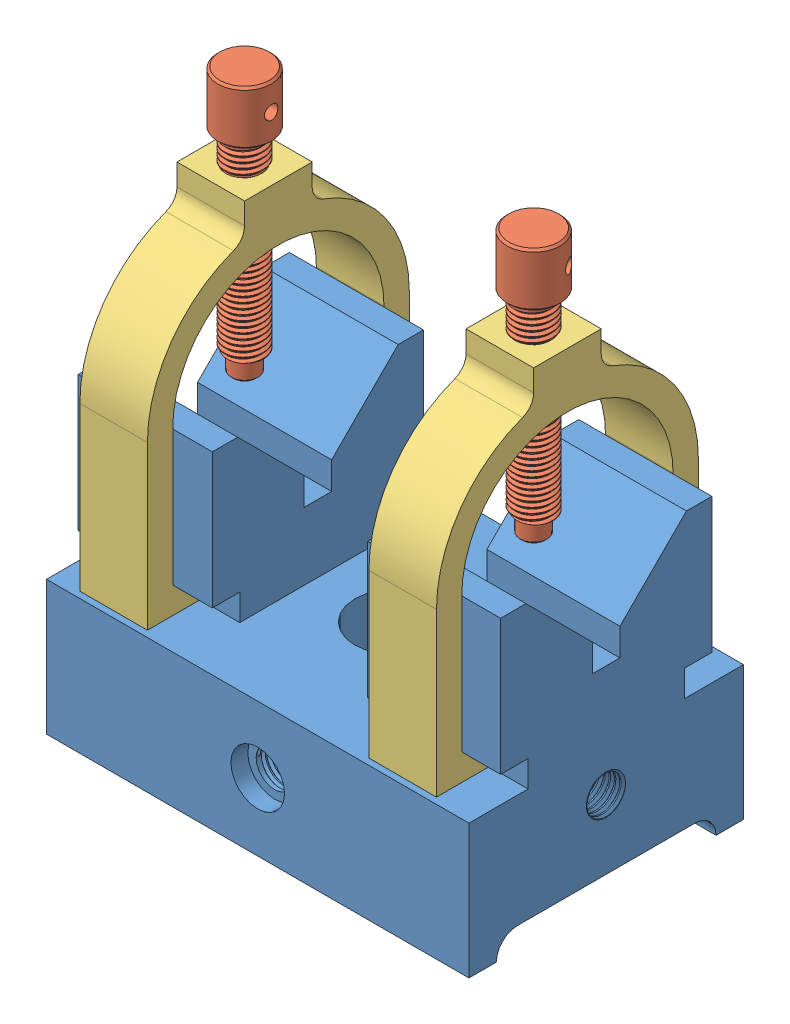
SolidWorks assembly Assem1, configuration Default. Lengths in mm.
Overall size (100.48 128.94 65).
5 component instances, 3 part files, 6 mates.
Components (placement in the parent):
- 1.Base-1: 1.Base [Default] at (-55.5589 15.6403 18.5643) size (100.48 70 65)
- 2.Fastener-1: 2.Fastener [Default] at (-22.7369 109.5842 18.5643) x (-0.457511 0 -0.889204) z (0.889204 0 -0.457511) size (12.7 62.7 12.7)
- 3.U-Clamp-1: 3.U-Clamp [Default] at (-22.7369 50.8903 18.5643) size (16 76.98 62)
- 3.U-Clamp-2: 3.U-Clamp [Default] at (-91.171 50.8903 18.5643) size (16 76.98 62)
- 2.Fastener-2: 2.Fastener [Default] at (-91.171 108.5473 18.5643) x (-0.023523 0 -0.999723) z (0.999723 0 -0.023523) size (12.7 62.7 12.7)
Mates (geometry in assembly coordinates):
- Coincident1: coincident anti-aligned: plane of 1.Base-1 through (-105.5589 12.3903 18.5643) normal (0 1 0); plane of 3.U-Clamp-1 through (-14.7369 12.3903 49.5643) normal (0 -1 0)
- Width1: width anti-aligned: plane of 3.U-Clamp-1 through (-14.7369 50.8903 49.5643) normal (0 0 1); plane of 1.Base-1 through (-14.7369 50.8903 -12.4357) normal (0 0 -1); plane of 3.U-Clamp-1 through (-105.5589 15.6403 -6.4357) normal (0 0 -1); plane of 1.Base-1 through (-105.5589 15.6403 43.5643) normal (0 0 1)
- Screw1: screw = 1 aligned: cylinder of 2.Fastener-1 through (-22.7369 51.8842 18.5643) axis (0 1 0) radius 4.625; cylinder of 3.U-Clamp-1 through (-22.7369 56.1903 18.5643) axis (0 1 0) radius 4.625
- Coincident2: coincident anti-aligned: plane of 1.Base-1 through (-105.5589 12.3903 18.5643) normal (0 1 0); plane of 3.U-Clamp-2 through (-83.171 12.3903 49.5643) normal (0 -1 0)
- Width2: width anti-aligned: plane of 3.U-Clamp-2 through (-83.171 50.8903 49.5643) normal (0 0 1); plane of 1.Base-1 through (-83.171 50.8903 -12.4357) normal (0 0 -1); plane of 3.U-Clamp-2 through (-105.5589 15.6403 -6.4357) normal (0 0 -1); plane of 1.Base-1 through (-105.5589 15.6403 43.5643) normal (0 0 1)
- Screw2: screw = 1 aligned: cylinder of 3.U-Clamp-2 through (-91.171 56.1903 18.5643) axis (0 1 0) radius 4.625; cylinder of 2.Fastener-2 through (-91.171 50.8473 18.5643) axis (0 1 0) radius 4.625
